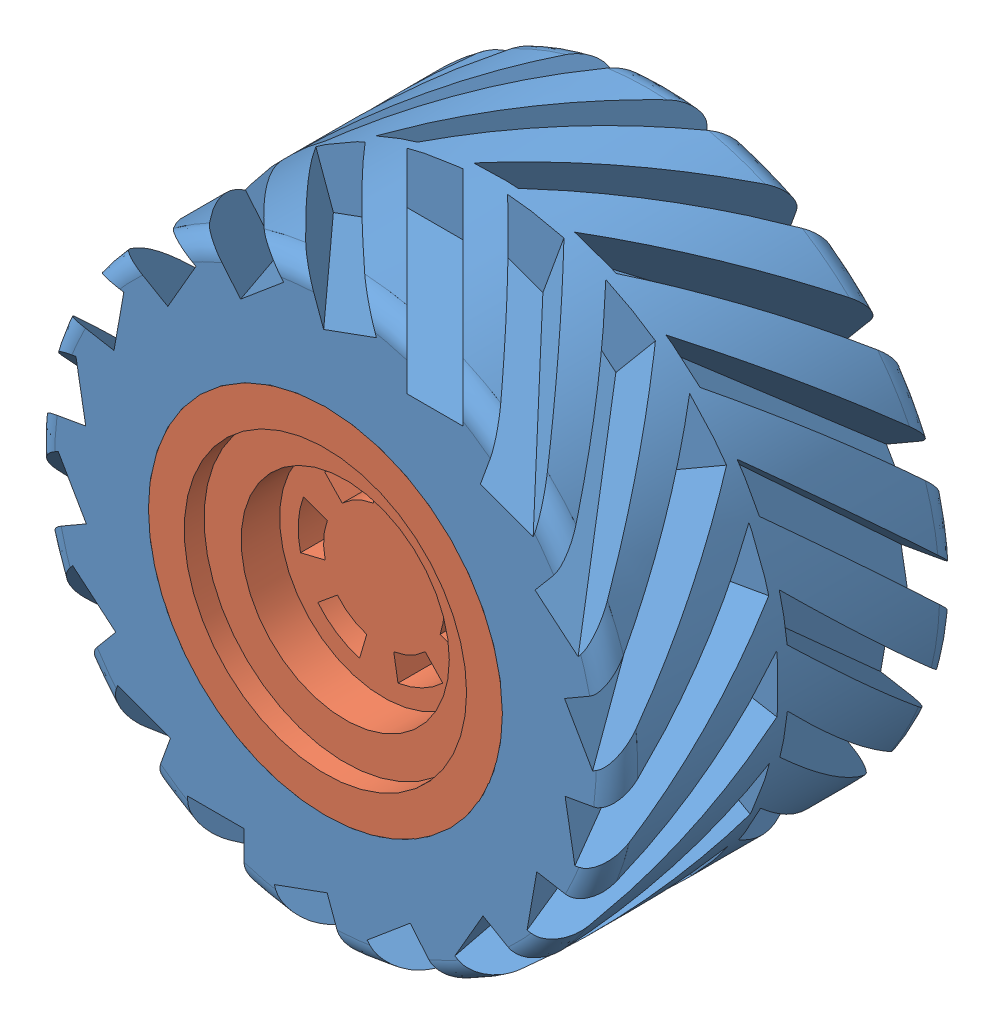
SolidWorks assembly Front Wheel Assembly, configuration Default. Lengths in mm.
Overall size (71.72 71.61 42.52).
2 component instances, 2 part files, 2 mates.
Components (placement in the parent):
- Tire 1-2: Tire 1 [Default] at (19.9119 41.7643 105.936) size (71.72 71.61 42.52)
- Front Wheel Hub-1: Front Wheel Hub [Default] at (19.9119 41.7643 126.891) size (43.18 43.18 41.91)
Mates (geometry in assembly coordinates):
- Concentric1: concentric aligned: circle of Tire 1-2; circle of Front Wheel Hub-1
- Coincident2: coincident aligned: plane of Tire 1-2 through (19.9119 41.7643 105.936) normal (0 0 -1); plane of Front Wheel Hub-1 through (19.9119 41.7643 105.936) normal (0 0 -1)
